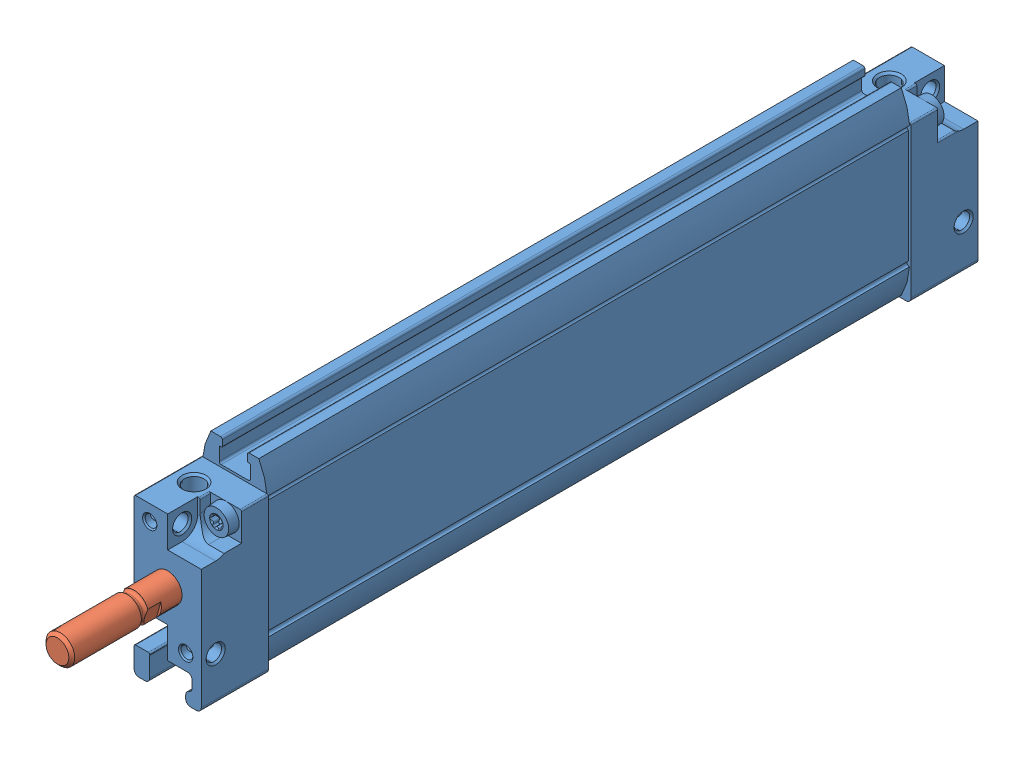
SolidWorks assembly 161229_DZF_12_100_A_P_A____0_, configuration Default. Lengths in mm.
Overall size (14 38 185.13).
4 component instances, 3 part files, 3 mates.
Components (placement in the parent):
- 161229_DZF_12_100_A_P_A____ZR_-1: 161229_DZF_12_100_A_P_A____ZR_ [Default] at origin size (14 38 162)
- 161229_DZF_12_100_A_P_A____KS_-1: 161229_DZF_12_100_A_P_A____KS_ [Default] at origin size (9 18 161.15)
- DIN_913___M5x5-1: DIN_913___M5x5 [Default] at (-2.5 4.75 -162) x (0 0 1) z (-1 0 0) size (5.13 5 5)
- DIN_913___M5x5-2: DIN_913___M5x5 [Default] at (2.5 -4.75 -162) x (0 0 1) z (-1 0 0) size (5.13 5 5)
Mates (geometry in assembly coordinates):
- LimitDistance2: limit distance = 0 mm aligned: plane of 161229_DZF_12_100_A_P_A____ZR_-1 through (0 0 -138.15) normal (0 0 1); plane of 161229_DZF_12_100_A_P_A____KS_-1 through (0 0 -138.15) normal (0 0 1)
- Coincident1: coincident aligned: line of 161229_DZF_12_100_A_P_A____ZR_-1 through (0 0 80.9) axis (0 0 -1); line of 161229_DZF_12_100_A_P_A____KS_-1 through (0 0 80.9) axis (0 0 -1)
- Angle3: planar angle = 0 rad aligned: plane of 161229_DZF_12_100_A_P_A____KS_-1 through (0 0 0) normal (1 0 0); plane of 161229_DZF_12_100_A_P_A____ZR_-1 through (0 0 0) normal (1 0 0)
